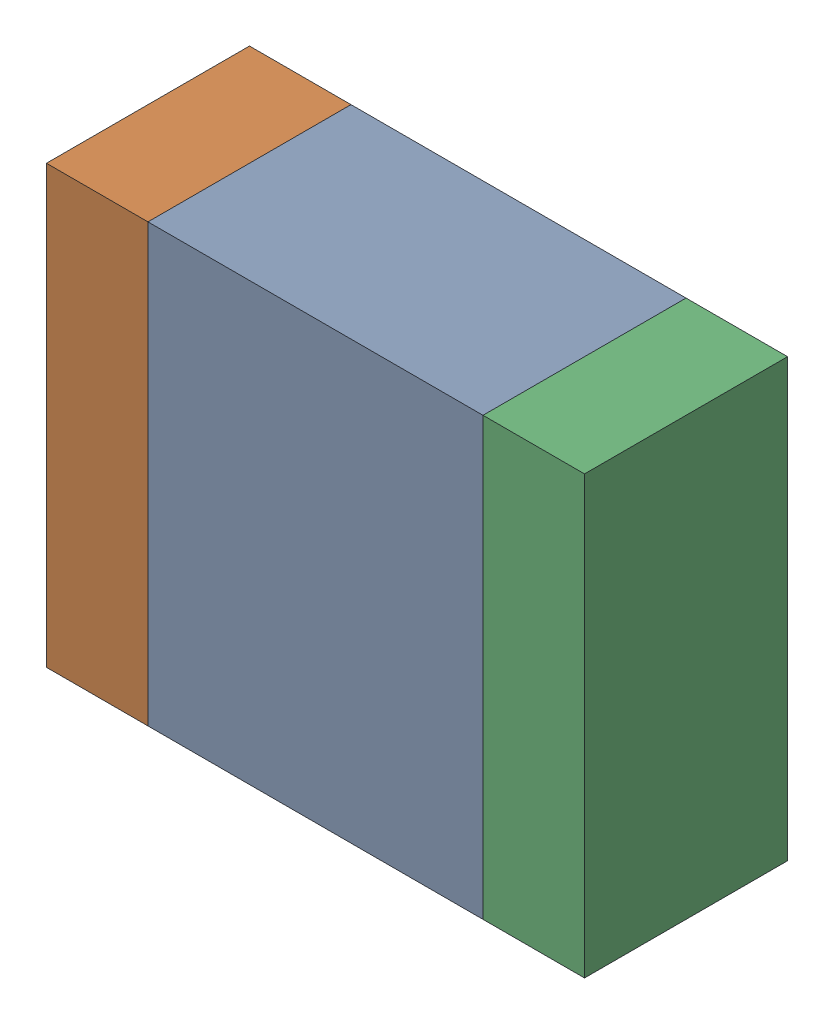
SolidWorks assembly L402PCB, configuration Default. Lengths in mm.
Overall size (2.65 2.15 1).
6 component instances, 2 part files, 0 mates.
Components (placement in the parent):
- 846486688-1: 846486688 [Default] at (87.6 79.4 0) size (1.65 2.15 1)
  - Extruded_25-1: Extruded_25 [Default] at origin size (1.65 2.15 1)
- 846486824-1: 846486824 [Default] at (86.525 79.4 0) size (0.5 2.15 1)
  - Extruded_26-1: Extruded_26 [Default] at origin size (0.5 2.15 1)
- 846486824-2: 846486824 [Default] at (88.675 79.4 0) size (0.5 2.15 1)
  - Extruded_26-1: Extruded_26 [Default] at origin size (0.5 2.15 1)
